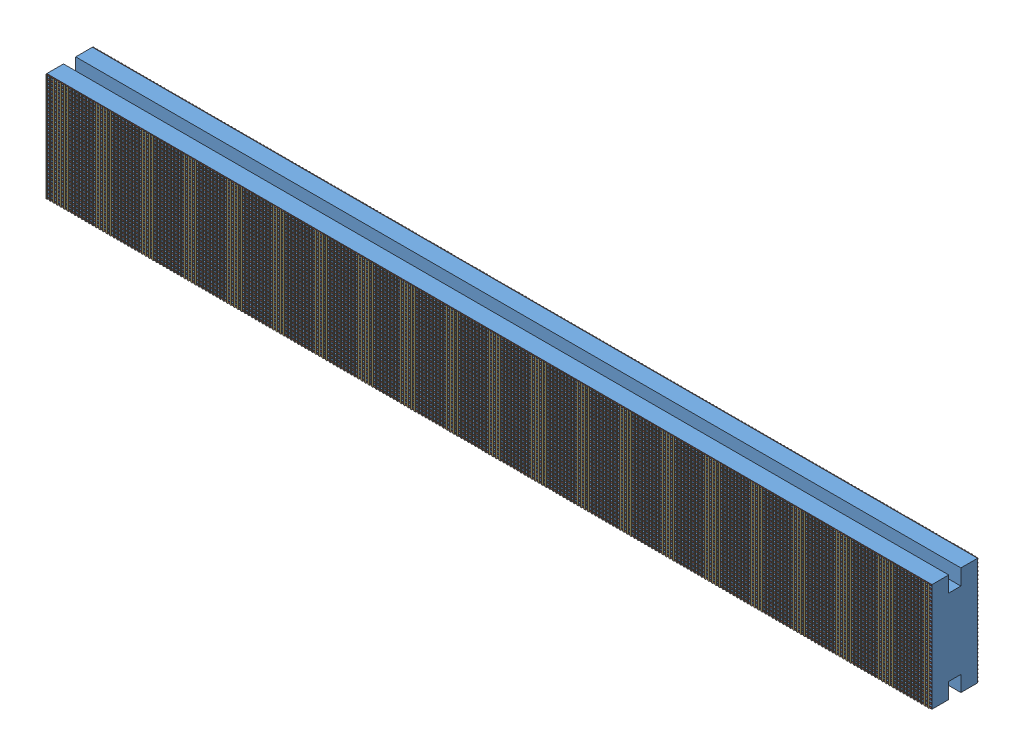
SolidWorks assembly B_neo, configuration Default. Lengths in mm.
Overall size (450 54.89 24).
282 component instances, 3 part files, 8 mates.
Components (placement in the parent):
- B_neo-1: B_neo [Default] at origin size (450 54.89 23.2)
- Part2^B_neo-1: Part2^B_neo [Default] x (0 0 1) z (-1 0 0) size (23.6 0.6 450) (virtual)
- Part3^B_neo-1: Part3^B_neo [Default] at (0 54.89 0) x (1 0 0) z (0 1 0) size (0.6 24 54.89) (virtual)
- Part2^B_neo-2: Part2^B_neo [Default] at (0 -1.8 0) x (0 0 1) z (-1 0 0) size (23.6 0.6 450) (virtual)
- Part2^B_neo-3: Part2^B_neo [Default] at (0 -3.6 0) x (0 0 1) z (-1 0 0) size (23.6 0.6 450) (virtual)
- Part2^B_neo-4: Part2^B_neo [Default] at (0 -5.4 0) x (0 0 1) z (-1 0 0) size (23.6 0.6 450) (virtual)
- Part2^B_neo-5: Part2^B_neo [Default] at (0 -7.2 0) x (0 0 1) z (-1 0 0) size (23.6 0.6 450) (virtual)
- Part2^B_neo-6: Part2^B_neo [Default] at (0 -9 0) x (0 0 1) z (-1 0 0) size (23.6 0.6 450) (virtual)
- Part2^B_neo-7: Part2^B_neo [Default] at (0 -10.8 0) x (0 0 1) z (-1 0 0) size (23.6 0.6 450) (virtual)
- Part2^B_neo-8: Part2^B_neo [Default] at (0 -12.6 0) x (0 0 1) z (-1 0 0) size (23.6 0.6 450) (virtual)
- Part2^B_neo-9: Part2^B_neo [Default] at (0 -14.4 0) x (0 0 1) z (-1 0 0) size (23.6 0.6 450) (virtual)
- Part2^B_neo-10: Part2^B_neo [Default] at (0 -16.2 0) x (0 0 1) z (-1 0 0) size (23.6 0.6 450) (virtual)
- Part2^B_neo-11: Part2^B_neo [Default] at (0 -18 0) x (0 0 1) z (-1 0 0) size (23.6 0.6 450) (virtual)
- Part2^B_neo-12: Part2^B_neo [Default] at (0 -19.8 0) x (0 0 1) z (-1 0 0) size (23.6 0.6 450) (virtual)
- Part2^B_neo-13: Part2^B_neo [Default] at (0 -21.6 0) x (0 0 1) z (-1 0 0) size (23.6 0.6 450) (virtual)
- Part2^B_neo-14: Part2^B_neo [Default] at (0 -23.4 0) x (0 0 1) z (-1 0 0) size (23.6 0.6 450) (virtual)
- Part2^B_neo-15: Part2^B_neo [Default] at (0 -25.2 0) x (0 0 1) z (-1 0 0) size (23.6 0.6 450) (virtual)
- Part2^B_neo-16: Part2^B_neo [Default] at (0 -27 0) x (0 0 1) z (-1 0 0) size (23.6 0.6 450) (virtual)
- Part2^B_neo-17: Part2^B_neo [Default] at (0 -28.8 0) x (0 0 1) z (-1 0 0) size (23.6 0.6 450) (virtual)
- Part2^B_neo-18: Part2^B_neo [Default] at (0 -30.6 0) x (0 0 1) z (-1 0 0) size (23.6 0.6 450) (virtual)
- Part2^B_neo-19: Part2^B_neo [Default] at (0 -32.4 0) x (0 0 1) z (-1 0 0) size (23.6 0.6 450) (virtual)
- Part2^B_neo-20: Part2^B_neo [Default] at (0 -34.2 0) x (0 0 1) z (-1 0 0) size (23.6 0.6 450) (virtual)
- Part2^B_neo-21: Part2^B_neo [Default] at (0 -36 0) x (0 0 1) z (-1 0 0) size (23.6 0.6 450) (virtual)
- Part2^B_neo-22: Part2^B_neo [Default] at (0 -37.8 0) x (0 0 1) z (-1 0 0) size (23.6 0.6 450) (virtual)
- Part2^B_neo-23: Part2^B_neo [Default] at (0 -39.6 0) x (0 0 1) z (-1 0 0) size (23.6 0.6 450) (virtual)
- Part2^B_neo-24: Part2^B_neo [Default] at (0 -41.4 0) x (0 0 1) z (-1 0 0) size (23.6 0.6 450) (virtual)
- Part2^B_neo-25: Part2^B_neo [Default] at (0 -43.2 0) x (0 0 1) z (-1 0 0) size (23.6 0.6 450) (virtual)
- Part2^B_neo-26: Part2^B_neo [Default] at (0 -45 0) x (0 0 1) z (-1 0 0) size (23.6 0.6 450) (virtual)
- Part2^B_neo-27: Part2^B_neo [Default] at (0 -46.8 0) x (0 0 1) z (-1 0 0) size (23.6 0.6 450) (virtual)
- Part2^B_neo-28: Part2^B_neo [Default] at (0 -48.6 0) x (0 0 1) z (-1 0 0) size (23.6 0.6 450) (virtual)
- Part2^B_neo-29: Part2^B_neo [Default] at (0 -50.4 0) x (0 0 1) z (-1 0 0) size (23.6 0.6 450) (virtual)
- Part2^B_neo-30: Part2^B_neo [Default] at (0 -52.2 0) x (0 0 1) z (-1 0 0) size (23.6 0.6 450) (virtual)
- Part2^B_neo-31: Part2^B_neo [Default] at (0 -54 0) x (0 0 1) z (-1 0 0) size (23.6 0.6 450) (virtual)
- Part3^B_neo-2: Part3^B_neo [Default] at (1.8 54.89 0) x (1 0 0) z (0 1 0) size (0.6 24 54.89) (virtual)
- Part3^B_neo-3: Part3^B_neo [Default] at (3.6 54.89 0) x (1 0 0) z (0 1 0) size (0.6 24 54.89) (virtual)
- Part3^B_neo-4: Part3^B_neo [Default] at (5.4 54.89 0) x (1 0 0) z (0 1 0) size (0.6 24 54.89) (virtual)
- Part3^B_neo-5: Part3^B_neo [Default] at (7.2 54.89 0) x (1 0 0) z (0 1 0) size (0.6 24 54.89) (virtual)
- Part3^B_neo-6: Part3^B_neo [Default] at (9 54.89 0) x (1 0 0) z (0 1 0) size (0.6 24 54.89) (virtual)
- Part3^B_neo-7: Part3^B_neo [Default] at (10.8 54.89 0) x (1 0 0) z (0 1 0) size (0.6 24 54.89) (virtual)
- Part3^B_neo-8: Part3^B_neo [Default] at (12.6 54.89 0) x (1 0 0) z (0 1 0) size (0.6 24 54.89) (virtual)
- Part3^B_neo-9: Part3^B_neo [Default] at (14.4 54.89 0) x (1 0 0) z (0 1 0) size (0.6 24 54.89) (virtual)
- Part3^B_neo-10: Part3^B_neo [Default] at (16.2 54.89 0) x (1 0 0) z (0 1 0) size (0.6 24 54.89) (virtual)
- Part3^B_neo-11: Part3^B_neo [Default] at (18 54.89 0) x (1 0 0) z (0 1 0) size (0.6 24 54.89) (virtual)
- Part3^B_neo-12: Part3^B_neo [Default] at (19.8 54.89 0) x (1 0 0) z (0 1 0) size (0.6 24 54.89) (virtual)
- Part3^B_neo-13: Part3^B_neo [Default] at (21.6 54.89 0) x (1 0 0) z (0 1 0) size (0.6 24 54.89) (virtual)
- Part3^B_neo-14: Part3^B_neo [Default] at (23.4 54.89 0) x (1 0 0) z (0 1 0) size (0.6 24 54.89) (virtual)
- Part3^B_neo-15: Part3^B_neo [Default] at (25.2 54.89 0) x (1 0 0) z (0 1 0) size (0.6 24 54.89) (virtual)
- Part3^B_neo-16: Part3^B_neo [Default] at (27 54.89 0) x (1 0 0) z (0 1 0) size (0.6 24 54.89) (virtual)
- Part3^B_neo-17: Part3^B_neo [Default] at (28.8 54.89 0) x (1 0 0) z (0 1 0) size (0.6 24 54.89) (virtual)
- Part3^B_neo-18: Part3^B_neo [Default] at (30.6 54.89 0) x (1 0 0) z (0 1 0) size (0.6 24 54.89) (virtual)
- Part3^B_neo-19: Part3^B_neo [Default] at (32.4 54.89 0) x (1 0 0) z (0 1 0) size (0.6 24 54.89) (virtual)
- Part3^B_neo-20: Part3^B_neo [Default] at (34.2 54.89 0) x (1 0 0) z (0 1 0) size (0.6 24 54.89) (virtual)
- Part3^B_neo-21: Part3^B_neo [Default] at (36 54.89 0) x (1 0 0) z (0 1 0) size (0.6 24 54.89) (virtual)
- Part3^B_neo-22: Part3^B_neo [Default] at (37.8 54.89 0) x (1 0 0) z (0 1 0) size (0.6 24 54.89) (virtual)
- Part3^B_neo-23: Part3^B_neo [Default] at (39.6 54.89 0) x (1 0 0) z (0 1 0) size (0.6 24 54.89) (virtual)
- Part3^B_neo-24: Part3^B_neo [Default] at (41.4 54.89 0) x (1 0 0) z (0 1 0) size (0.6 24 54.89) (virtual)
- Part3^B_neo-25: Part3^B_neo [Default] at (43.2 54.89 0) x (1 0 0) z (0 1 0) size (0.6 24 54.89) (virtual)
- Part3^B_neo-26: Part3^B_neo [Default] at (45 54.89 0) x (1 0 0) z (0 1 0) size (0.6 24 54.89) (virtual)
- Part3^B_neo-27: Part3^B_neo [Default] at (46.8 54.89 0) x (1 0 0) z (0 1 0) size (0.6 24 54.89) (virtual)
- Part3^B_neo-28: Part3^B_neo [Default] at (48.6 54.89 0) x (1 0 0) z (0 1 0) size (0.6 24 54.89) (virtual)
- Part3^B_neo-29: Part3^B_neo [Default] at (50.4 54.89 0) x (1 0 0) z (0 1 0) size (0.6 24 54.89) (virtual)
- Part3^B_neo-30: Part3^B_neo [Default] at (52.2 54.89 0) x (1 0 0) z (0 1 0) size (0.6 24 54.89) (virtual)
- Part3^B_neo-31: Part3^B_neo [Default] at (54 54.89 0) x (1 0 0) z (0 1 0) size (0.6 24 54.89) (virtual)
- Part3^B_neo-32: Part3^B_neo [Default] at (55.8 54.89 0) x (1 0 0) z (0 1 0) size (0.6 24 54.89) (virtual)
- Part3^B_neo-33: Part3^B_neo [Default] at (57.6 54.89 0) x (1 0 0) z (0 1 0) size (0.6 24 54.89) (virtual)
- Part3^B_neo-34: Part3^B_neo [Default] at (59.4 54.89 0) x (1 0 0) z (0 1 0) size (0.6 24 54.89) (virtual)
- Part3^B_neo-35: Part3^B_neo [Default] at (61.2 54.89 0) x (1 0 0) z (0 1 0) size (0.6 24 54.89) (virtual)
- Part3^B_neo-36: Part3^B_neo [Default] at (63 54.89 0) x (1 0 0) z (0 1 0) size (0.6 24 54.89) (virtual)
- Part3^B_neo-37: Part3^B_neo [Default] at (64.8 54.89 0) x (1 0 0) z (0 1 0) size (0.6 24 54.89) (virtual)
- Part3^B_neo-38: Part3^B_neo [Default] at (66.6 54.89 0) x (1 0 0) z (0 1 0) size (0.6 24 54.89) (virtual)
- Part3^B_neo-39: Part3^B_neo [Default] at (68.4 54.89 0) x (1 0 0) z (0 1 0) size (0.6 24 54.89) (virtual)
- Part3^B_neo-40: Part3^B_neo [Default] at (70.2 54.89 0) x (1 0 0) z (0 1 0) size (0.6 24 54.89) (virtual)
- Part3^B_neo-41: Part3^B_neo [Default] at (72 54.89 0) x (1 0 0) z (0 1 0) size (0.6 24 54.89) (virtual)
- Part3^B_neo-42: Part3^B_neo [Default] at (73.8 54.89 0) x (1 0 0) z (0 1 0) size (0.6 24 54.89) (virtual)
- Part3^B_neo-43: Part3^B_neo [Default] at (75.6 54.89 0) x (1 0 0) z (0 1 0) size (0.6 24 54.89) (virtual)
- Part3^B_neo-44: Part3^B_neo [Default] at (77.4 54.89 0) x (1 0 0) z (0 1 0) size (0.6 24 54.89) (virtual)
- Part3^B_neo-45: Part3^B_neo [Default] at (79.2 54.89 0) x (1 0 0) z (0 1 0) size (0.6 24 54.89) (virtual)
- Part3^B_neo-46: Part3^B_neo [Default] at (81 54.89 0) x (1 0 0) z (0 1 0) size (0.6 24 54.89) (virtual)
- Part3^B_neo-47: Part3^B_neo [Default] at (82.8 54.89 0) x (1 0 0) z (0 1 0) size (0.6 24 54.89) (virtual)
- Part3^B_neo-48: Part3^B_neo [Default] at (84.6 54.89 0) x (1 0 0) z (0 1 0) size (0.6 24 54.89) (virtual)
- Part3^B_neo-49: Part3^B_neo [Default] at (86.4 54.89 0) x (1 0 0) z (0 1 0) size (0.6 24 54.89) (virtual)
- Part3^B_neo-50: Part3^B_neo [Default] at (88.2 54.89 0) x (1 0 0) z (0 1 0) size (0.6 24 54.89) (virtual)
- Part3^B_neo-51: Part3^B_neo [Default] at (90 54.89 0) x (1 0 0) z (0 1 0) size (0.6 24 54.89) (virtual)
- Part3^B_neo-52: Part3^B_neo [Default] at (91.8 54.89 0) x (1 0 0) z (0 1 0) size (0.6 24 54.89) (virtual)
- Part3^B_neo-53: Part3^B_neo [Default] at (93.6 54.89 0) x (1 0 0) z (0 1 0) size (0.6 24 54.89) (virtual)
- Part3^B_neo-54: Part3^B_neo [Default] at (95.4 54.89 0) x (1 0 0) z (0 1 0) size (0.6 24 54.89) (virtual)
- Part3^B_neo-55: Part3^B_neo [Default] at (97.2 54.89 0) x (1 0 0) z (0 1 0) size (0.6 24 54.89) (virtual)
- Part3^B_neo-56: Part3^B_neo [Default] at (99 54.89 0) x (1 0 0) z (0 1 0) size (0.6 24 54.89) (virtual)
- Part3^B_neo-57: Part3^B_neo [Default] at (100.8 54.89 0) x (1 0 0) z (0 1 0) size (0.6 24 54.89) (virtual)
- Part3^B_neo-58: Part3^B_neo [Default] at (102.6 54.89 0) x (1 0 0) z (0 1 0) size (0.6 24 54.89) (virtual)
- Part3^B_neo-59: Part3^B_neo [Default] at (104.4 54.89 0) x (1 0 0) z (0 1 0) size (0.6 24 54.89) (virtual)
- Part3^B_neo-60: Part3^B_neo [Default] at (106.2 54.89 0) x (1 0 0) z (0 1 0) size (0.6 24 54.89) (virtual)
- Part3^B_neo-61: Part3^B_neo [Default] at (108 54.89 0) x (1 0 0) z (0 1 0) size (0.6 24 54.89) (virtual)
- Part3^B_neo-62: Part3^B_neo [Default] at (109.8 54.89 0) x (1 0 0) z (0 1 0) size (0.6 24 54.89) (virtual)
- Part3^B_neo-63: Part3^B_neo [Default] at (111.6 54.89 0) x (1 0 0) z (0 1 0) size (0.6 24 54.89) (virtual)
- Part3^B_neo-64: Part3^B_neo [Default] at (113.4 54.89 0) x (1 0 0) z (0 1 0) size (0.6 24 54.89) (virtual)
- Part3^B_neo-65: Part3^B_neo [Default] at (115.2 54.89 0) x (1 0 0) z (0 1 0) size (0.6 24 54.89) (virtual)
- Part3^B_neo-66: Part3^B_neo [Default] at (117 54.89 0) x (1 0 0) z (0 1 0) size (0.6 24 54.89) (virtual)
- Part3^B_neo-67: Part3^B_neo [Default] at (118.8 54.89 0) x (1 0 0) z (0 1 0) size (0.6 24 54.89) (virtual)
- Part3^B_neo-68: Part3^B_neo [Default] at (120.6 54.89 0) x (1 0 0) z (0 1 0) size (0.6 24 54.89) (virtual)
- Part3^B_neo-69: Part3^B_neo [Default] at (122.4 54.89 0) x (1 0 0) z (0 1 0) size (0.6 24 54.89) (virtual)
- Part3^B_neo-70: Part3^B_neo [Default] at (124.2 54.89 0) x (1 0 0) z (0 1 0) size (0.6 24 54.89) (virtual)
- Part3^B_neo-71: Part3^B_neo [Default] at (126 54.89 0) x (1 0 0) z (0 1 0) size (0.6 24 54.89) (virtual)
- Part3^B_neo-72: Part3^B_neo [Default] at (127.8 54.89 0) x (1 0 0) z (0 1 0) size (0.6 24 54.89) (virtual)
- Part3^B_neo-73: Part3^B_neo [Default] at (129.6 54.89 0) x (1 0 0) z (0 1 0) size (0.6 24 54.89) (virtual)
- Part3^B_neo-74: Part3^B_neo [Default] at (131.4 54.89 0) x (1 0 0) z (0 1 0) size (0.6 24 54.89) (virtual)
- Part3^B_neo-75: Part3^B_neo [Default] at (133.2 54.89 0) x (1 0 0) z (0 1 0) size (0.6 24 54.89) (virtual)
- Part3^B_neo-76: Part3^B_neo [Default] at (135 54.89 0) x (1 0 0) z (0 1 0) size (0.6 24 54.89) (virtual)
- Part3^B_neo-77: Part3^B_neo [Default] at (136.8 54.89 0) x (1 0 0) z (0 1 0) size (0.6 24 54.89) (virtual)
- Part3^B_neo-78: Part3^B_neo [Default] at (138.6 54.89 0) x (1 0 0) z (0 1 0) size (0.6 24 54.89) (virtual)
- Part3^B_neo-79: Part3^B_neo [Default] at (140.4 54.89 0) x (1 0 0) z (0 1 0) size (0.6 24 54.89) (virtual)
- Part3^B_neo-80: Part3^B_neo [Default] at (142.2 54.89 0) x (1 0 0) z (0 1 0) size (0.6 24 54.89) (virtual)
- Part3^B_neo-81: Part3^B_neo [Default] at (144 54.89 0) x (1 0 0) z (0 1 0) size (0.6 24 54.89) (virtual)
- Part3^B_neo-82: Part3^B_neo [Default] at (145.8 54.89 0) x (1 0 0) z (0 1 0) size (0.6 24 54.89) (virtual)
- Part3^B_neo-83: Part3^B_neo [Default] at (147.6 54.89 0) x (1 0 0) z (0 1 0) size (0.6 24 54.89) (virtual)
- Part3^B_neo-84: Part3^B_neo [Default] at (149.4 54.89 0) x (1 0 0) z (0 1 0) size (0.6 24 54.89) (virtual)
- Part3^B_neo-85: Part3^B_neo [Default] at (151.2 54.89 0) x (1 0 0) z (0 1 0) size (0.6 24 54.89) (virtual)
- Part3^B_neo-86: Part3^B_neo [Default] at (153 54.89 0) x (1 0 0) z (0 1 0) size (0.6 24 54.89) (virtual)
- Part3^B_neo-87: Part3^B_neo [Default] at (154.8 54.89 0) x (1 0 0) z (0 1 0) size (0.6 24 54.89) (virtual)
- Part3^B_neo-88: Part3^B_neo [Default] at (156.6 54.89 0) x (1 0 0) z (0 1 0) size (0.6 24 54.89) (virtual)
- Part3^B_neo-89: Part3^B_neo [Default] at (158.4 54.89 0) x (1 0 0) z (0 1 0) size (0.6 24 54.89) (virtual)
- Part3^B_neo-90: Part3^B_neo [Default] at (160.2 54.89 0) x (1 0 0) z (0 1 0) size (0.6 24 54.89) (virtual)
- Part3^B_neo-91: Part3^B_neo [Default] at (162 54.89 0) x (1 0 0) z (0 1 0) size (0.6 24 54.89) (virtual)
- Part3^B_neo-92: Part3^B_neo [Default] at (163.8 54.89 0) x (1 0 0) z (0 1 0) size (0.6 24 54.89) (virtual)
- Part3^B_neo-93: Part3^B_neo [Default] at (165.6 54.89 0) x (1 0 0) z (0 1 0) size (0.6 24 54.89) (virtual)
- Part3^B_neo-94: Part3^B_neo [Default] at (167.4 54.89 0) x (1 0 0) z (0 1 0) size (0.6 24 54.89) (virtual)
- Part3^B_neo-95: Part3^B_neo [Default] at (169.2 54.89 0) x (1 0 0) z (0 1 0) size (0.6 24 54.89) (virtual)
- Part3^B_neo-96: Part3^B_neo [Default] at (171 54.89 0) x (1 0 0) z (0 1 0) size (0.6 24 54.89) (virtual)
- Part3^B_neo-97: Part3^B_neo [Default] at (172.8 54.89 0) x (1 0 0) z (0 1 0) size (0.6 24 54.89) (virtual)
- Part3^B_neo-98: Part3^B_neo [Default] at (174.6 54.89 0) x (1 0 0) z (0 1 0) size (0.6 24 54.89) (virtual)
- Part3^B_neo-99: Part3^B_neo [Default] at (176.4 54.89 0) x (1 0 0) z (0 1 0) size (0.6 24 54.89) (virtual)
- Part3^B_neo-100: Part3^B_neo [Default] at (178.2 54.89 0) x (1 0 0) z (0 1 0) size (0.6 24 54.89) (virtual)
- Part3^B_neo-101: Part3^B_neo [Default] at (180 54.89 0) x (1 0 0) z (0 1 0) size (0.6 24 54.89) (virtual)
- Part3^B_neo-102: Part3^B_neo [Default] at (181.8 54.89 0) x (1 0 0) z (0 1 0) size (0.6 24 54.89) (virtual)
- Part3^B_neo-103: Part3^B_neo [Default] at (183.6 54.89 0) x (1 0 0) z (0 1 0) size (0.6 24 54.89) (virtual)
- Part3^B_neo-104: Part3^B_neo [Default] at (185.4 54.89 0) x (1 0 0) z (0 1 0) size (0.6 24 54.89) (virtual)
- Part3^B_neo-105: Part3^B_neo [Default] at (187.2 54.89 0) x (1 0 0) z (0 1 0) size (0.6 24 54.89) (virtual)
- Part3^B_neo-106: Part3^B_neo [Default] at (189 54.89 0) x (1 0 0) z (0 1 0) size (0.6 24 54.89) (virtual)
- Part3^B_neo-107: Part3^B_neo [Default] at (190.8 54.89 0) x (1 0 0) z (0 1 0) size (0.6 24 54.89) (virtual)
- Part3^B_neo-108: Part3^B_neo [Default] at (192.6 54.89 0) x (1 0 0) z (0 1 0) size (0.6 24 54.89) (virtual)
- Part3^B_neo-109: Part3^B_neo [Default] at (194.4 54.89 0) x (1 0 0) z (0 1 0) size (0.6 24 54.89) (virtual)
- Part3^B_neo-110: Part3^B_neo [Default] at (196.2 54.89 0) x (1 0 0) z (0 1 0) size (0.6 24 54.89) (virtual)
- Part3^B_neo-111: Part3^B_neo [Default] at (198 54.89 0) x (1 0 0) z (0 1 0) size (0.6 24 54.89) (virtual)
- Part3^B_neo-112: Part3^B_neo [Default] at (199.8 54.89 0) x (1 0 0) z (0 1 0) size (0.6 24 54.89) (virtual)
- Part3^B_neo-113: Part3^B_neo [Default] at (201.6 54.89 0) x (1 0 0) z (0 1 0) size (0.6 24 54.89) (virtual)
- Part3^B_neo-114: Part3^B_neo [Default] at (203.4 54.89 0) x (1 0 0) z (0 1 0) size (0.6 24 54.89) (virtual)
- Part3^B_neo-115: Part3^B_neo [Default] at (205.2 54.89 0) x (1 0 0) z (0 1 0) size (0.6 24 54.89) (virtual)
- Part3^B_neo-116: Part3^B_neo [Default] at (207 54.89 0) x (1 0 0) z (0 1 0) size (0.6 24 54.89) (virtual)
- Part3^B_neo-117: Part3^B_neo [Default] at (208.8 54.89 0) x (1 0 0) z (0 1 0) size (0.6 24 54.89) (virtual)
- Part3^B_neo-118: Part3^B_neo [Default] at (210.6 54.89 0) x (1 0 0) z (0 1 0) size (0.6 24 54.89) (virtual)
- Part3^B_neo-119: Part3^B_neo [Default] at (212.4 54.89 0) x (1 0 0) z (0 1 0) size (0.6 24 54.89) (virtual)
- Part3^B_neo-120: Part3^B_neo [Default] at (214.2 54.89 0) x (1 0 0) z (0 1 0) size (0.6 24 54.89) (virtual)
- Part3^B_neo-121: Part3^B_neo [Default] at (216 54.89 0) x (1 0 0) z (0 1 0) size (0.6 24 54.89) (virtual)
- Part3^B_neo-122: Part3^B_neo [Default] at (217.8 54.89 0) x (1 0 0) z (0 1 0) size (0.6 24 54.89) (virtual)
- Part3^B_neo-123: Part3^B_neo [Default] at (219.6 54.89 0) x (1 0 0) z (0 1 0) size (0.6 24 54.89) (virtual)
- Part3^B_neo-124: Part3^B_neo [Default] at (221.4 54.89 0) x (1 0 0) z (0 1 0) size (0.6 24 54.89) (virtual)
- Part3^B_neo-125: Part3^B_neo [Default] at (223.2 54.89 0) x (1 0 0) z (0 1 0) size (0.6 24 54.89) (virtual)
- Part3^B_neo-126: Part3^B_neo [Default] at (225 54.89 0) x (1 0 0) z (0 1 0) size (0.6 24 54.89) (virtual)
- Part3^B_neo-127: Part3^B_neo [Default] at (226.8 54.89 0) x (1 0 0) z (0 1 0) size (0.6 24 54.89) (virtual)
- Part3^B_neo-128: Part3^B_neo [Default] at (228.6 54.89 0) x (1 0 0) z (0 1 0) size (0.6 24 54.89) (virtual)
- Part3^B_neo-129: Part3^B_neo [Default] at (230.4 54.89 0) x (1 0 0) z (0 1 0) size (0.6 24 54.89) (virtual)
- Part3^B_neo-130: Part3^B_neo [Default] at (232.2 54.89 0) x (1 0 0) z (0 1 0) size (0.6 24 54.89) (virtual)
- Part3^B_neo-131: Part3^B_neo [Default] at (234 54.89 0) x (1 0 0) z (0 1 0) size (0.6 24 54.89) (virtual)
- Part3^B_neo-132: Part3^B_neo [Default] at (235.8 54.89 0) x (1 0 0) z (0 1 0) size (0.6 24 54.89) (virtual)
- Part3^B_neo-133: Part3^B_neo [Default] at (237.6 54.89 0) x (1 0 0) z (0 1 0) size (0.6 24 54.89) (virtual)
- Part3^B_neo-134: Part3^B_neo [Default] at (239.4 54.89 0) x (1 0 0) z (0 1 0) size (0.6 24 54.89) (virtual)
- Part3^B_neo-135: Part3^B_neo [Default] at (241.2 54.89 0) x (1 0 0) z (0 1 0) size (0.6 24 54.89) (virtual)
- Part3^B_neo-136: Part3^B_neo [Default] at (243 54.89 0) x (1 0 0) z (0 1 0) size (0.6 24 54.89) (virtual)
- Part3^B_neo-137: Part3^B_neo [Default] at (244.8 54.89 0) x (1 0 0) z (0 1 0) size (0.6 24 54.89) (virtual)
- Part3^B_neo-138: Part3^B_neo [Default] at (246.6 54.89 0) x (1 0 0) z (0 1 0) size (0.6 24 54.89) (virtual)
- Part3^B_neo-139: Part3^B_neo [Default] at (248.4 54.89 0) x (1 0 0) z (0 1 0) size (0.6 24 54.89) (virtual)
- Part3^B_neo-140: Part3^B_neo [Default] at (250.2 54.89 0) x (1 0 0) z (0 1 0) size (0.6 24 54.89) (virtual)
- Part3^B_neo-141: Part3^B_neo [Default] at (252 54.89 0) x (1 0 0) z (0 1 0) size (0.6 24 54.89) (virtual)
- Part3^B_neo-142: Part3^B_neo [Default] at (253.8 54.89 0) x (1 0 0) z (0 1 0) size (0.6 24 54.89) (virtual)
- Part3^B_neo-143: Part3^B_neo [Default] at (255.6 54.89 0) x (1 0 0) z (0 1 0) size (0.6 24 54.89) (virtual)
- Part3^B_neo-144: Part3^B_neo [Default] at (257.4 54.89 0) x (1 0 0) z (0 1 0) size (0.6 24 54.89) (virtual)
- Part3^B_neo-145: Part3^B_neo [Default] at (259.2 54.89 0) x (1 0 0) z (0 1 0) size (0.6 24 54.89) (virtual)
- Part3^B_neo-146: Part3^B_neo [Default] at (261 54.89 0) x (1 0 0) z (0 1 0) size (0.6 24 54.89) (virtual)
- Part3^B_neo-147: Part3^B_neo [Default] at (262.8 54.89 0) x (1 0 0) z (0 1 0) size (0.6 24 54.89) (virtual)
- Part3^B_neo-148: Part3^B_neo [Default] at (264.6 54.89 0) x (1 0 0) z (0 1 0) size (0.6 24 54.89) (virtual)
- Part3^B_neo-149: Part3^B_neo [Default] at (266.4 54.89 0) x (1 0 0) z (0 1 0) size (0.6 24 54.89) (virtual)
- Part3^B_neo-150: Part3^B_neo [Default] at (268.2 54.89 0) x (1 0 0) z (0 1 0) size (0.6 24 54.89) (virtual)
- Part3^B_neo-151: Part3^B_neo [Default] at (270 54.89 0) x (1 0 0) z (0 1 0) size (0.6 24 54.89) (virtual)
- Part3^B_neo-152: Part3^B_neo [Default] at (271.8 54.89 0) x (1 0 0) z (0 1 0) size (0.6 24 54.89) (virtual)
- Part3^B_neo-153: Part3^B_neo [Default] at (273.6 54.89 0) x (1 0 0) z (0 1 0) size (0.6 24 54.89) (virtual)
- Part3^B_neo-154: Part3^B_neo [Default] at (275.4 54.89 0) x (1 0 0) z (0 1 0) size (0.6 24 54.89) (virtual)
- Part3^B_neo-155: Part3^B_neo [Default] at (277.2 54.89 0) x (1 0 0) z (0 1 0) size (0.6 24 54.89) (virtual)
- Part3^B_neo-156: Part3^B_neo [Default] at (279 54.89 0) x (1 0 0) z (0 1 0) size (0.6 24 54.89) (virtual)
- Part3^B_neo-157: Part3^B_neo [Default] at (280.8 54.89 0) x (1 0 0) z (0 1 0) size (0.6 24 54.89) (virtual)
- Part3^B_neo-158: Part3^B_neo [Default] at (282.6 54.89 0) x (1 0 0) z (0 1 0) size (0.6 24 54.89) (virtual)
- Part3^B_neo-159: Part3^B_neo [Default] at (284.4 54.89 0) x (1 0 0) z (0 1 0) size (0.6 24 54.89) (virtual)
- Part3^B_neo-160: Part3^B_neo [Default] at (286.2 54.89 0) x (1 0 0) z (0 1 0) size (0.6 24 54.89) (virtual)
- Part3^B_neo-161: Part3^B_neo [Default] at (288 54.89 0) x (1 0 0) z (0 1 0) size (0.6 24 54.89) (virtual)
- Part3^B_neo-162: Part3^B_neo [Default] at (289.8 54.89 0) x (1 0 0) z (0 1 0) size (0.6 24 54.89) (virtual)
- Part3^B_neo-163: Part3^B_neo [Default] at (291.6 54.89 0) x (1 0 0) z (0 1 0) size (0.6 24 54.89) (virtual)
- Part3^B_neo-164: Part3^B_neo [Default] at (293.4 54.89 0) x (1 0 0) z (0 1 0) size (0.6 24 54.89) (virtual)
- Part3^B_neo-165: Part3^B_neo [Default] at (295.2 54.89 0) x (1 0 0) z (0 1 0) size (0.6 24 54.89) (virtual)
- Part3^B_neo-166: Part3^B_neo [Default] at (297 54.89 0) x (1 0 0) z (0 1 0) size (0.6 24 54.89) (virtual)
- Part3^B_neo-167: Part3^B_neo [Default] at (298.8 54.89 0) x (1 0 0) z (0 1 0) size (0.6 24 54.89) (virtual)
- Part3^B_neo-168: Part3^B_neo [Default] at (300.6 54.89 0) x (1 0 0) z (0 1 0) size (0.6 24 54.89) (virtual)
- Part3^B_neo-169: Part3^B_neo [Default] at (302.4 54.89 0) x (1 0 0) z (0 1 0) size (0.6 24 54.89) (virtual)
- Part3^B_neo-170: Part3^B_neo [Default] at (304.2 54.89 0) x (1 0 0) z (0 1 0) size (0.6 24 54.89) (virtual)
- Part3^B_neo-171: Part3^B_neo [Default] at (306 54.89 0) x (1 0 0) z (0 1 0) size (0.6 24 54.89) (virtual)
- Part3^B_neo-172: Part3^B_neo [Default] at (307.8 54.89 0) x (1 0 0) z (0 1 0) size (0.6 24 54.89) (virtual)
- Part3^B_neo-173: Part3^B_neo [Default] at (309.6 54.89 0) x (1 0 0) z (0 1 0) size (0.6 24 54.89) (virtual)
- Part3^B_neo-174: Part3^B_neo [Default] at (311.4 54.89 0) x (1 0 0) z (0 1 0) size (0.6 24 54.89) (virtual)
- Part3^B_neo-175: Part3^B_neo [Default] at (313.2 54.89 0) x (1 0 0) z (0 1 0) size (0.6 24 54.89) (virtual)
- Part3^B_neo-176: Part3^B_neo [Default] at (315 54.89 0) x (1 0 0) z (0 1 0) size (0.6 24 54.89) (virtual)
- Part3^B_neo-177: Part3^B_neo [Default] at (316.8 54.89 0) x (1 0 0) z (0 1 0) size (0.6 24 54.89) (virtual)
- Part3^B_neo-178: Part3^B_neo [Default] at (318.6 54.89 0) x (1 0 0) z (0 1 0) size (0.6 24 54.89) (virtual)
- Part3^B_neo-179: Part3^B_neo [Default] at (320.4 54.89 0) x (1 0 0) z (0 1 0) size (0.6 24 54.89) (virtual)
- Part3^B_neo-180: Part3^B_neo [Default] at (322.2 54.89 0) x (1 0 0) z (0 1 0) size (0.6 24 54.89) (virtual)
- Part3^B_neo-181: Part3^B_neo [Default] at (324 54.89 0) x (1 0 0) z (0 1 0) size (0.6 24 54.89) (virtual)
- Part3^B_neo-182: Part3^B_neo [Default] at (325.8 54.89 0) x (1 0 0) z (0 1 0) size (0.6 24 54.89) (virtual)
- Part3^B_neo-183: Part3^B_neo [Default] at (327.6 54.89 0) x (1 0 0) z (0 1 0) size (0.6 24 54.89) (virtual)
- Part3^B_neo-184: Part3^B_neo [Default] at (329.4 54.89 0) x (1 0 0) z (0 1 0) size (0.6 24 54.89) (virtual)
- Part3^B_neo-185: Part3^B_neo [Default] at (331.2 54.89 0) x (1 0 0) z (0 1 0) size (0.6 24 54.89) (virtual)
- Part3^B_neo-186: Part3^B_neo [Default] at (333 54.89 0) x (1 0 0) z (0 1 0) size (0.6 24 54.89) (virtual)
- Part3^B_neo-187: Part3^B_neo [Default] at (334.8 54.89 0) x (1 0 0) z (0 1 0) size (0.6 24 54.89) (virtual)
- Part3^B_neo-188: Part3^B_neo [Default] at (336.6 54.89 0) x (1 0 0) z (0 1 0) size (0.6 24 54.89) (virtual)
- Part3^B_neo-189: Part3^B_neo [Default] at (338.4 54.89 0) x (1 0 0) z (0 1 0) size (0.6 24 54.89) (virtual)
- Part3^B_neo-190: Part3^B_neo [Default] at (340.2 54.89 0) x (1 0 0) z (0 1 0) size (0.6 24 54.89) (virtual)
- Part3^B_neo-191: Part3^B_neo [Default] at (342 54.89 0) x (1 0 0) z (0 1 0) size (0.6 24 54.89) (virtual)
- Part3^B_neo-192: Part3^B_neo [Default] at (343.8 54.89 0) x (1 0 0) z (0 1 0) size (0.6 24 54.89) (virtual)
- Part3^B_neo-193: Part3^B_neo [Default] at (345.6 54.89 0) x (1 0 0) z (0 1 0) size (0.6 24 54.89) (virtual)
- Part3^B_neo-194: Part3^B_neo [Default] at (347.4 54.89 0) x (1 0 0) z (0 1 0) size (0.6 24 54.89) (virtual)
- Part3^B_neo-195: Part3^B_neo [Default] at (349.2 54.89 0) x (1 0 0) z (0 1 0) size (0.6 24 54.89) (virtual)
- Part3^B_neo-196: Part3^B_neo [Default] at (351 54.89 0) x (1 0 0) z (0 1 0) size (0.6 24 54.89) (virtual)
- Part3^B_neo-197: Part3^B_neo [Default] at (352.8 54.89 0) x (1 0 0) z (0 1 0) size (0.6 24 54.89) (virtual)
- Part3^B_neo-198: Part3^B_neo [Default] at (354.6 54.89 0) x (1 0 0) z (0 1 0) size (0.6 24 54.89) (virtual)
- Part3^B_neo-199: Part3^B_neo [Default] at (356.4 54.89 0) x (1 0 0) z (0 1 0) size (0.6 24 54.89) (virtual)
- Part3^B_neo-200: Part3^B_neo [Default] at (358.2 54.89 0) x (1 0 0) z (0 1 0) size (0.6 24 54.89) (virtual)
- Part3^B_neo-201: Part3^B_neo [Default] at (360 54.89 0) x (1 0 0) z (0 1 0) size (0.6 24 54.89) (virtual)
- Part3^B_neo-202: Part3^B_neo [Default] at (361.8 54.89 0) x (1 0 0) z (0 1 0) size (0.6 24 54.89) (virtual)
- Part3^B_neo-203: Part3^B_neo [Default] at (363.6 54.89 0) x (1 0 0) z (0 1 0) size (0.6 24 54.89) (virtual)
- Part3^B_neo-204: Part3^B_neo [Default] at (365.4 54.89 0) x (1 0 0) z (0 1 0) size (0.6 24 54.89) (virtual)
- Part3^B_neo-205: Part3^B_neo [Default] at (367.2 54.89 0) x (1 0 0) z (0 1 0) size (0.6 24 54.89) (virtual)
- Part3^B_neo-206: Part3^B_neo [Default] at (369 54.89 0) x (1 0 0) z (0 1 0) size (0.6 24 54.89) (virtual)
- Part3^B_neo-207: Part3^B_neo [Default] at (370.8 54.89 0) x (1 0 0) z (0 1 0) size (0.6 24 54.89) (virtual)
- Part3^B_neo-208: Part3^B_neo [Default] at (372.6 54.89 0) x (1 0 0) z (0 1 0) size (0.6 24 54.89) (virtual)
- Part3^B_neo-209: Part3^B_neo [Default] at (374.4 54.89 0) x (1 0 0) z (0 1 0) size (0.6 24 54.89) (virtual)
- Part3^B_neo-210: Part3^B_neo [Default] at (376.2 54.89 0) x (1 0 0) z (0 1 0) size (0.6 24 54.89) (virtual)
- Part3^B_neo-211: Part3^B_neo [Default] at (378 54.89 0) x (1 0 0) z (0 1 0) size (0.6 24 54.89) (virtual)
- Part3^B_neo-212: Part3^B_neo [Default] at (379.8 54.89 0) x (1 0 0) z (0 1 0) size (0.6 24 54.89) (virtual)
- Part3^B_neo-213: Part3^B_neo [Default] at (381.6 54.89 0) x (1 0 0) z (0 1 0) size (0.6 24 54.89) (virtual)
- Part3^B_neo-214: Part3^B_neo [Default] at (383.4 54.89 0) x (1 0 0) z (0 1 0) size (0.6 24 54.89) (virtual)
- Part3^B_neo-215: Part3^B_neo [Default] at (385.2 54.89 0) x (1 0 0) z (0 1 0) size (0.6 24 54.89) (virtual)
- Part3^B_neo-216: Part3^B_neo [Default] at (387 54.89 0) x (1 0 0) z (0 1 0) size (0.6 24 54.89) (virtual)
- Part3^B_neo-217: Part3^B_neo [Default] at (388.8 54.89 0) x (1 0 0) z (0 1 0) size (0.6 24 54.89) (virtual)
- Part3^B_neo-218: Part3^B_neo [Default] at (390.6 54.89 0) x (1 0 0) z (0 1 0) size (0.6 24 54.89) (virtual)
- Part3^B_neo-219: Part3^B_neo [Default] at (392.4 54.89 0) x (1 0 0) z (0 1 0) size (0.6 24 54.89) (virtual)
- Part3^B_neo-220: Part3^B_neo [Default] at (394.2 54.89 0) x (1 0 0) z (0 1 0) size (0.6 24 54.89) (virtual)
- Part3^B_neo-221: Part3^B_neo [Default] at (396 54.89 0) x (1 0 0) z (0 1 0) size (0.6 24 54.89) (virtual)
- Part3^B_neo-222: Part3^B_neo [Default] at (397.8 54.89 0) x (1 0 0) z (0 1 0) size (0.6 24 54.89) (virtual)
- Part3^B_neo-223: Part3^B_neo [Default] at (399.6 54.89 0) x (1 0 0) z (0 1 0) size (0.6 24 54.89) (virtual)
- Part3^B_neo-224: Part3^B_neo [Default] at (401.4 54.89 0) x (1 0 0) z (0 1 0) size (0.6 24 54.89) (virtual)
- Part3^B_neo-225: Part3^B_neo [Default] at (403.2 54.89 0) x (1 0 0) z (0 1 0) size (0.6 24 54.89) (virtual)
- Part3^B_neo-226: Part3^B_neo [Default] at (405 54.89 0) x (1 0 0) z (0 1 0) size (0.6 24 54.89) (virtual)
- Part3^B_neo-227: Part3^B_neo [Default] at (406.8 54.89 0) x (1 0 0) z (0 1 0) size (0.6 24 54.89) (virtual)
- Part3^B_neo-228: Part3^B_neo [Default] at (408.6 54.89 0) x (1 0 0) z (0 1 0) size (0.6 24 54.89) (virtual)
- Part3^B_neo-229: Part3^B_neo [Default] at (410.4 54.89 0) x (1 0 0) z (0 1 0) size (0.6 24 54.89) (virtual)
- Part3^B_neo-230: Part3^B_neo [Default] at (412.2 54.89 0) x (1 0 0) z (0 1 0) size (0.6 24 54.89) (virtual)
- Part3^B_neo-231: Part3^B_neo [Default] at (414 54.89 0) x (1 0 0) z (0 1 0) size (0.6 24 54.89) (virtual)
- Part3^B_neo-232: Part3^B_neo [Default] at (415.8 54.89 0) x (1 0 0) z (0 1 0) size (0.6 24 54.89) (virtual)
- Part3^B_neo-233: Part3^B_neo [Default] at (417.6 54.89 0) x (1 0 0) z (0 1 0) size (0.6 24 54.89) (virtual)
- Part3^B_neo-234: Part3^B_neo [Default] at (419.4 54.89 0) x (1 0 0) z (0 1 0) size (0.6 24 54.89) (virtual)
- Part3^B_neo-235: Part3^B_neo [Default] at (421.2 54.89 0) x (1 0 0) z (0 1 0) size (0.6 24 54.89) (virtual)
- Part3^B_neo-236: Part3^B_neo [Default] at (423 54.89 0) x (1 0 0) z (0 1 0) size (0.6 24 54.89) (virtual)
- Part3^B_neo-237: Part3^B_neo [Default] at (424.8 54.89 0) x (1 0 0) z (0 1 0) size (0.6 24 54.89) (virtual)
- Part3^B_neo-238: Part3^B_neo [Default] at (426.6 54.89 0) x (1 0 0) z (0 1 0) size (0.6 24 54.89) (virtual)
- Part3^B_neo-239: Part3^B_neo [Default] at (428.4 54.89 0) x (1 0 0) z (0 1 0) size (0.6 24 54.89) (virtual)
- Part3^B_neo-240: Part3^B_neo [Default] at (430.2 54.89 0) x (1 0 0) z (0 1 0) size (0.6 24 54.89) (virtual)
- Part3^B_neo-241: Part3^B_neo [Default] at (432 54.89 0) x (1 0 0) z (0 1 0) size (0.6 24 54.89) (virtual)
- Part3^B_neo-242: Part3^B_neo [Default] at (433.8 54.89 0) x (1 0 0) z (0 1 0) size (0.6 24 54.89) (virtual)
- Part3^B_neo-243: Part3^B_neo [Default] at (435.6 54.89 0) x (1 0 0) z (0 1 0) size (0.6 24 54.89) (virtual)
- Part3^B_neo-244: Part3^B_neo [Default] at (437.4 54.89 0) x (1 0 0) z (0 1 0) size (0.6 24 54.89) (virtual)
- Part3^B_neo-245: Part3^B_neo [Default] at (439.2 54.89 0) x (1 0 0) z (0 1 0) size (0.6 24 54.89) (virtual)
- Part3^B_neo-246: Part3^B_neo [Default] at (441 54.89 0) x (1 0 0) z (0 1 0) size (0.6 24 54.89) (virtual)
- Part3^B_neo-247: Part3^B_neo [Default] at (442.8 54.89 0) x (1 0 0) z (0 1 0) size (0.6 24 54.89) (virtual)
- Part3^B_neo-248: Part3^B_neo [Default] at (444.6 54.89 0) x (1 0 0) z (0 1 0) size (0.6 24 54.89) (virtual)
- Part3^B_neo-249: Part3^B_neo [Default] at (446.4 54.89 0) x (1 0 0) z (0 1 0) size (0.6 24 54.89) (virtual)
- Part3^B_neo-250: Part3^B_neo [Default] at (448.2 54.89 0) x (1 0 0) z (0 1 0) size (0.6 24 54.89) (virtual)
Mates (geometry in assembly coordinates):
- InPlace1: in place: plane of B_neo-1 through (0 0 0) normal (-1 0 0); plane of Part2^B_neo-1 through (0 0 0) normal (-1 0 0); moOrthogonalPlaneRef_w of B_neo-1 through (0 0 0) normal (-1 0 0); plane of Part2^B_neo-1 through (0 0 0) normal (0 1 0); plane of B_neo-1 through (0 0 0) normal (-1 0 0); plane of Part2^B_neo-1 through (0 0 0) normal (0 0 1); plane of B_neo-1 through (0 0 0) normal (-1 0 0); unknown of Part2^B_neo-1
- Coincident1: coincident aligned: plane of B_neo-1; plane of Part2^B_neo-1
- Coincident2: coincident aligned: moOrthogonalPlaneRef_w of B_neo-1 through (0 0 0) normal (0 1 0); plane of Part2^B_neo-1 through (0 0 0) normal (0 1 0)
- Coincident3: coincident anti-aligned: moOrthogonalPlaneRef_w of B_neo-1 through (0 0 0) normal (0 0 -1); plane of Part2^B_neo-1 through (0 0 0) normal (0 0 1)
- InPlace2: in place: plane of B_neo-1 through (450 79.89 0) normal (0 1 0); plane of ? through (0 79.89 0) normal (0 1 0); plane of B_neo-1 through (450 79.89 0) normal (0 1 0); plane of ? through (0 79.89 0) normal (0 0 -1); plane of B_neo-1 through (450 79.89 0) normal (0 1 0); plane of ? through (0 79.89 0) normal (1 0 0); plane of B_neo-1 through (450 54.89 0) normal (0 1 0); unknown of Part3^B_neo-1
- Coincident4: coincident aligned: plane of B_neo-1; plane of Part3^B_neo-1
- Coincident5: coincident aligned: moOrthogonalPlaneRef_w of B_neo-1 through (0 54.89 0) normal (0 0 -1); plane of Part3^B_neo-1 through (0 54.89 0) normal (0 0 -1)
- Coincident6: coincident anti-aligned: moOrthogonalPlaneRef_w of B_neo-1 through (0 54.89 0) normal (-1 0 0); plane of Part3^B_neo-1 through (0 54.89 0) normal (1 0 0)
